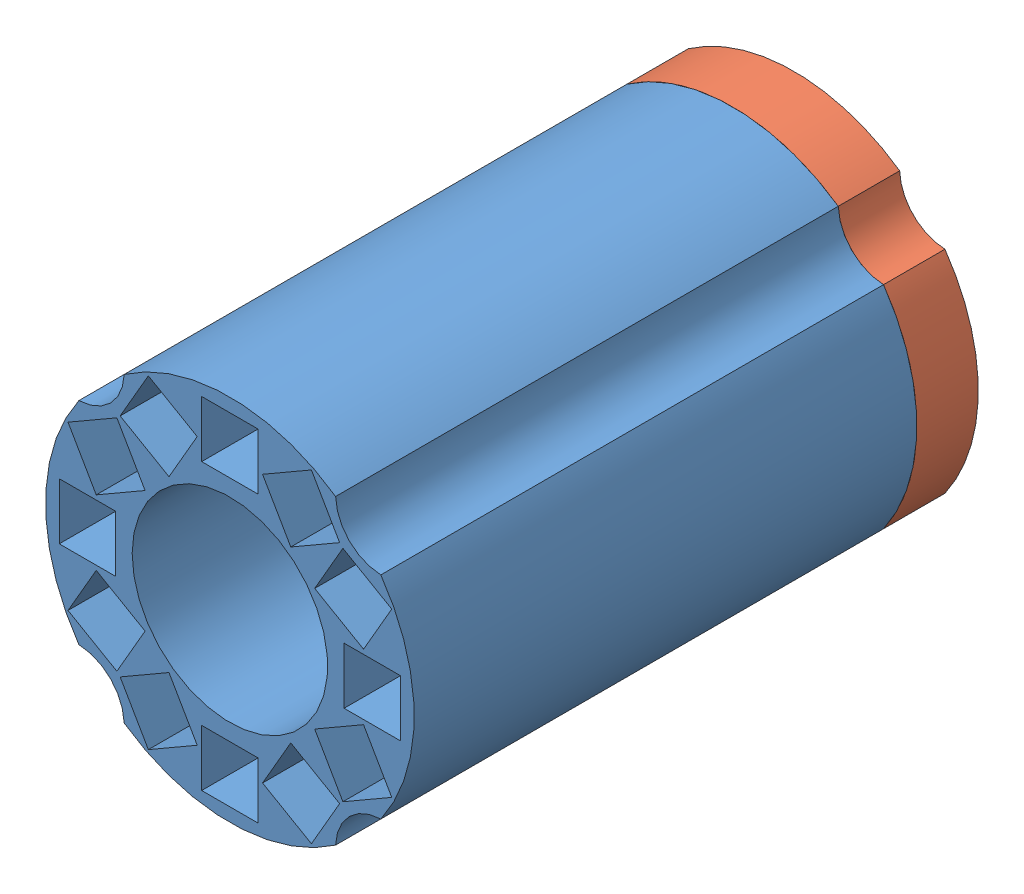
SolidWorks assembly Assem1, configuration Default. Lengths in mm.
Overall size (66 66 101).
2 component instances, 2 part files, 1 mates.
Components (placement in the parent):
- inside_ring-1: inside_ring [Default] at (15.6645 51.9573 75.1538) size (66 66 90)
- inside_ring_cap-1: inside_ring_cap [Default] at (15.6645 51.9573 64.1538) size (66 66 11)
Mates (geometry in assembly coordinates):
- Coincident1: coincident: circle of inside_ring-1; circle of inside_ring_cap-1
